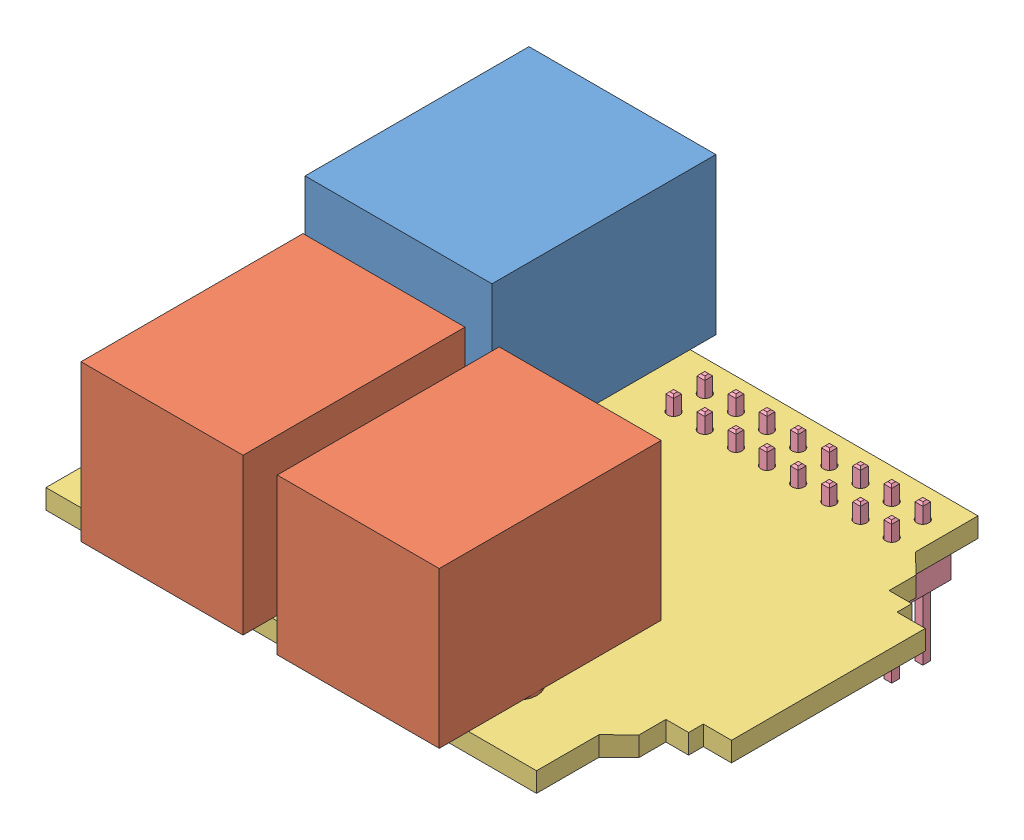
SolidWorks assembly IO-Base-PCB-Mouser-Assembly, configuration Default. Lengths in mm.
Overall size (51.6 23.02 40.49).
10 component instances, 4 part files, 4 mates.
Components (placement in the parent):
- IO-Base-PCB-Mouser-1: IO-Base-PCB-Mouser [Default] x (1 0 0) z (0 -1 0) size (51.6 40.49 17.83)
  - IO-Base-Mouser.STEP-1: IO-Base-Mouser.STEP [Default] at origin size (51.6 40.49 17.83)
    - SS-90000-001.STEP-1: SS-90000-001.STEP [Default] at (13.5 -18.5 -0.05) x (-1 0 0) z (0 0 -1) size (15.24 18.26 17.83)
      - COMPOUND.STEP-1: COMPOUND.STEP [Default] at origin size (15.24 18.26 17.83)
    - SS-90000-003.STEP-1: SS-90000-003.STEP [Default] at (8.83 -9.122 -0.05) x (1 0 0) z (0 0 -1) size (13.21 18.1 17.8)
      - COMPOUND-0.STEP-1: COMPOUND-0.STEP [Default] at origin size (13.21 18.1 17.8)
    - SS-90000-003.STEP-2: SS-90000-003.STEP [Default] at (24.83 -9.122 -0.05) x (1 0 0) z (0 0 -1) size (13.21 18.1 17.8)
      - COMPOUND-0.STEP-1: COMPOUND-0.STEP [Default] at origin size (13.21 18.1 17.8)
    - IO-Base-mouser PCB.STEP-1: IO-Base-mouser PCB.STEP [Default] at origin size (51.6 36 1.6)
- PinHeader_2x08_P2.54mm_Vertical-1: PinHeader_2x08_P2.54mm_Vertical [Default] at (20.22 -1.6 -28.4) x (0 0 1) z (0 -1 0) size (5.08 20.32 11.54)
Mates (geometry in assembly coordinates):
- Coincident1: coincident: line of IO-Base-PCB-Mouser-1 through (42.2318 0 -27.13) axis (-1 0 0); plane of PinHeader_2x08_P2.54mm_Vertical-1 through (20.22 -1.6 -27.13) normal (0 0 1)
- Coincident2: coincident: plane of IO-Base-PCB-Mouser-1/IO-Base-Mouser.STEP-1/IO-Base-mouser PCB.STEP-1 through (20 -1.6 -12.9) normal (0 -1 0); plane of PinHeader_2x08_P2.54mm_Vertical-1 through (29.11 -1.6 -27.13) normal (0 1 0)
- Concentric1: concentric anti-aligned: cylinder of IO-Base-PCB-Mouser-1/IO-Base-Mouser.STEP-1/IO-Base-mouser PCB.STEP-1 through (38 0.8 -25.86) axis (0 -1 0) radius 0.5; circle of PinHeader_2x08_P2.54mm_Vertical-1
- Concentric2: concentric anti-aligned: circle of IO-Base-PCB-Mouser-1/IO-Base-Mouser.STEP-1/IO-Base-mouser PCB.STEP-1; circle of PinHeader_2x08_P2.54mm_Vertical-1
